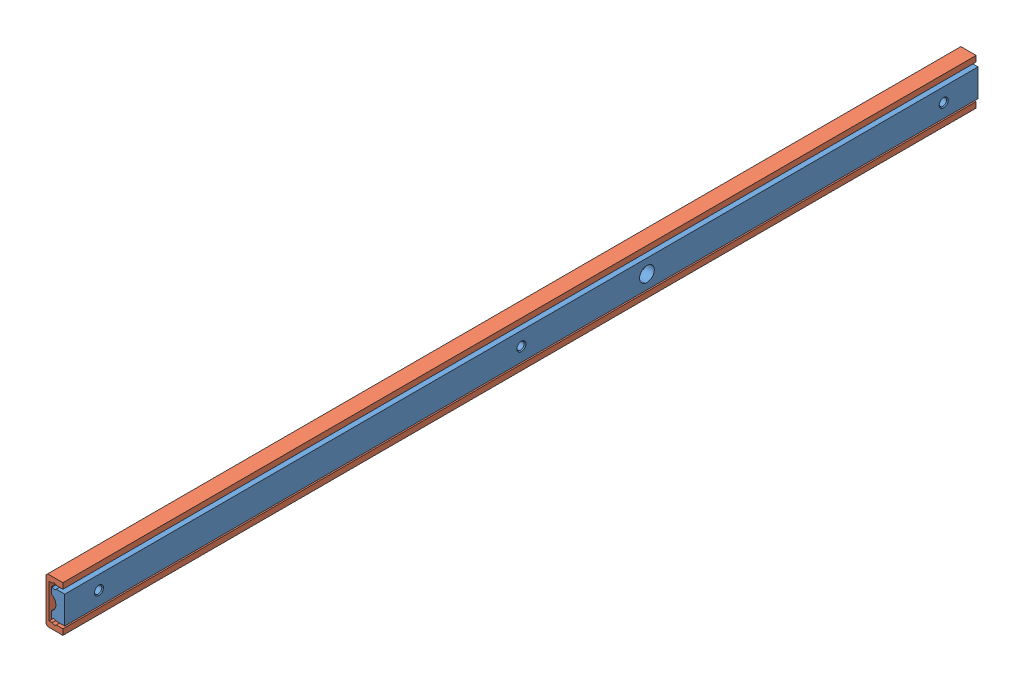
SolidWorks assembly Assem2, configuration Default. Lengths in mm.
Overall size (9.5 22.1 600).
2 component instances, 2 part files, 0 mates.
Components (placement in the parent):
- SAR2-40_r-1: SAR2-40_r [Default] at origin size (6 12.1 400)
- SAR2-40_b-1: SAR2-40_b [Default] at (5 -3.95 0) size (7.4 20 400)
